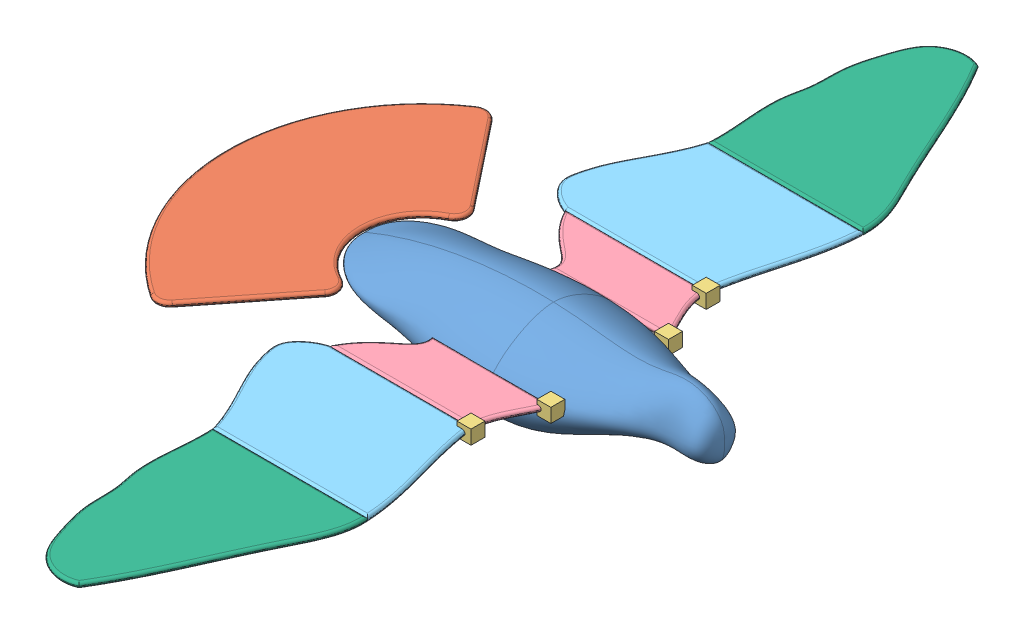
SolidWorks assembly pigeon_assembly_3, configuration Default. Lengths in mm.
Overall size (355.83 69.51 657.25).
16 component instances, 6 part files, 31 mates.
Components (placement in the parent):
- torso_contours-1: torso_contours [Default] at (-321.9795 -52 0) x (0 0 1) z (-1 0 0) size (94.74 69.51 256.9)
- tail-1: tail [Default] at (-323.7845 -54 0) x (0 0 1) z (-1 0 0) size (235.93 4 125.9)
- ghost_component-1: ghost_component [Default] at (-81.9795 0 -42) x (0 0 1) z (-1 0 0) size (10 10 10)
- ghost_component-2: ghost_component [Default] at (-81.9795 0 -42) x (0 0 1) z (-1 0 0) size (10 10 10)
- upper_wing-2: upper_wing [Default] at (-217.3123 -2 -322.6835) x (0 0 1) z (-1 0 0) size (42 8.51 121.5)
- ghost_component-3: ghost_component [Default] at (-97.0339 0 -83.9981) x (0 0 1) z (-1 0 0) size (10 10 10)
- ghost_component-4: ghost_component [Default] at (-97.0339 0 -83.9981) x (0 0 1) z (-1 0 0) size (10 10 10)
- mid_wing-1: mid_wing [Default] at (-217.3123 -2 -322.6835) x (0 0 1) z (-1 0 0) size (102.24 9.28 147.46)
- hand_wing-1: hand_wing [Default] at (-217.3123 -2 -322.6835) x (0 0 1) z (-1 0 0) size (157.2 28.03 132.9)
- ghost_component-13: ghost_component [Default] at (-81.9795 0 42) x (0 0 -1) z (-1 0 0) size (10 10 10)
- ghost_component-14: ghost_component [Default] at (-81.9795 0 42) x (0 0 -1) z (-1 0 0) size (10 10 10)
- upper_wing-5: upper_wing [Default] at (-217.3123 2 322.6835) x (0 0 -1) z (-1 0 0) size (42 8.51 121.5)
- ghost_component-15: ghost_component [Default] at (-97.0339 0 83.9981) x (0 0 -1) z (-1 0 0) size (10 10 10)
- ghost_component-16: ghost_component [Default] at (-97.0339 0 83.9981) x (0 0 -1) z (-1 0 0) size (10 10 10)
- mid_wing-4: mid_wing [Default] at (-217.3123 2 322.6835) x (0 0 -1) z (-1 0 0) size (102.24 9.28 147.46)
- hand_wing-4: hand_wing [Default] at (-217.3123 2 322.6835) x (0 0 -1) z (-1 0 0) size (157.2 28.03 132.9)
Mates (geometry in assembly coordinates):
- Coincident3: coordinate: point of torso_contours-1; point of assembly
- Coincident9: coincident aligned: line of torso_contours-1 through (-229.9795 0 -52.1057) axis (0 0 1); line of tail-1 through (-229.9795 0 -44.8451) axis (0 0 1)
- Coincident10: coincident aligned: plane of torso_contours-1 through (-256.6828 0 0) normal (0 0 1); plane of tail-1 through (-258.4878 0 0) normal (0 0 1)
- Coincident12: coincident aligned: line of torso_contours-1 through (-269.5633 0 -42) axis (1 0 0); line of ghost_component-1 through (-87.4795 0 -42) axis (1 0 0)
- Coincident13: coincident aligned: plane of torso_contours-1 through (-81.9795 -52 0) normal (-1 0 0); plane of ghost_component-1 through (-81.9795 0 -42) normal (-1 0 0)
- Coincident15: coincident aligned: line of ghost_component-1 through (-81.9795 0 -36.5) axis (0 0 -1); line of ghost_component-2 through (-81.9795 0 -36.5) axis (0 0 -1)
- Coincident17: coincident anti-aligned: line of ghost_component-2 through (-81.9795 10.5 -42) axis (0 -1 0); line of upper_wing-2 through (-81.9795 0 -42) axis (0 1 0)
- Coincident18: coincident: plane of ghost_component-2; point of upper_wing-2
- Coincident19: coincident aligned: plane of ghost_component-1 through (-81.9795 0 -42) normal (0 0 1); plane of ghost_component-2 through (-81.9795 0 -42) normal (0 0 1)
- Coincident21: coincident aligned: line of upper_wing-2 through (-197.7314 0 -83.9981) axis (1 0 0); line of ghost_component-3 through (-102.5339 0 -83.9981) axis (1 0 0)
- Coincident22: coincident: point of upper_wing-2; plane of ghost_component-3 through (-97.0339 0 -83.9981) normal (-1 0 0)
- Coincident24: coincident aligned: line of ghost_component-3 through (-97.0339 0 -78.4981) axis (0 0 -1); line of ghost_component-4 through (-97.0339 0 -78.4981) axis (0 0 -1)
- Coincident26: coincident anti-aligned: line of ghost_component-4 through (-97.0339 10.5 -83.9981) axis (0 -1 0); line of mid_wing-1 through (-97.0339 0 -83.9981) axis (0 1 0)
- Coincident27: coincident: plane of ghost_component-4; point of mid_wing-1
- Coincident28: coincident aligned: plane of ghost_component-3 through (-97.0339 0 -83.9981) normal (0 0 1); plane of ghost_component-4 through (-97.0339 0 -83.9981) normal (0 0 1)
- Coincident30: coincident aligned: line of mid_wing-1 through (-188.6353 0 -176.9607) axis (1 0 0); line of hand_wing-1 through (-188.6353 0 -176.9607) axis (1 0 0)
- Coincident31: coincident: point of mid_wing-1; point of hand_wing-1
- Coincident33: coincident aligned: line of torso_contours-1 through (-269.5633 0 42) axis (1 0 0); line of ghost_component-13 through (-87.4795 0 42) axis (1 0 0)
- Coincident34: coincident aligned: plane of torso_contours-1 through (-81.9795 -52 0) normal (-1 0 0); plane of ghost_component-13 through (-81.9795 0 42) normal (-1 0 0)
- Coincident36: coincident aligned: line of ghost_component-13 through (-81.9795 0 36.5) axis (0 0 1); line of ghost_component-14 through (-81.9795 0 36.5) axis (0 0 1)
- Coincident39: coincident anti-aligned: line of ghost_component-14 through (-81.9795 -10.5 42) axis (0 1 0); line of upper_wing-5 through (-81.9795 0 42) axis (0 -1 0)
- Coincident40: coincident: plane of ghost_component-14; point of upper_wing-5
- Coincident41: coincident aligned: plane of ghost_component-13; plane of ghost_component-14
- Coincident43: coincident aligned: line of upper_wing-5 through (-197.7314 0 83.9981) axis (1 0 0); line of ghost_component-15 through (-102.5339 0 83.9981) axis (1 0 0)
- Coincident44: coincident: point of upper_wing-5; plane of ghost_component-15 through (-97.0339 0 83.9981) normal (-1 0 0)
- Coincident46: coincident aligned: line of ghost_component-15 through (-97.0339 0 78.4981) axis (0 0 1); line of ghost_component-16 through (-97.0339 0 78.4981) axis (0 0 1)
- Coincident48: coincident anti-aligned: line of ghost_component-16 through (-97.0339 -10.5 83.9981) axis (0 1 0); line of mid_wing-4 through (-97.0339 0 83.9981) axis (0 -1 0)
- Coincident49: coincident: plane of ghost_component-16; point of mid_wing-4
- Coincident50: coincident aligned: plane of ghost_component-15; plane of ghost_component-16
- Coincident52: coincident aligned: line of mid_wing-4 through (-188.6353 0 176.9607) axis (1 0 0); line of hand_wing-4 through (-188.6353 0 176.9607) axis (1 0 0)
- Coincident53: coincident: point of mid_wing-4; point of hand_wing-4
